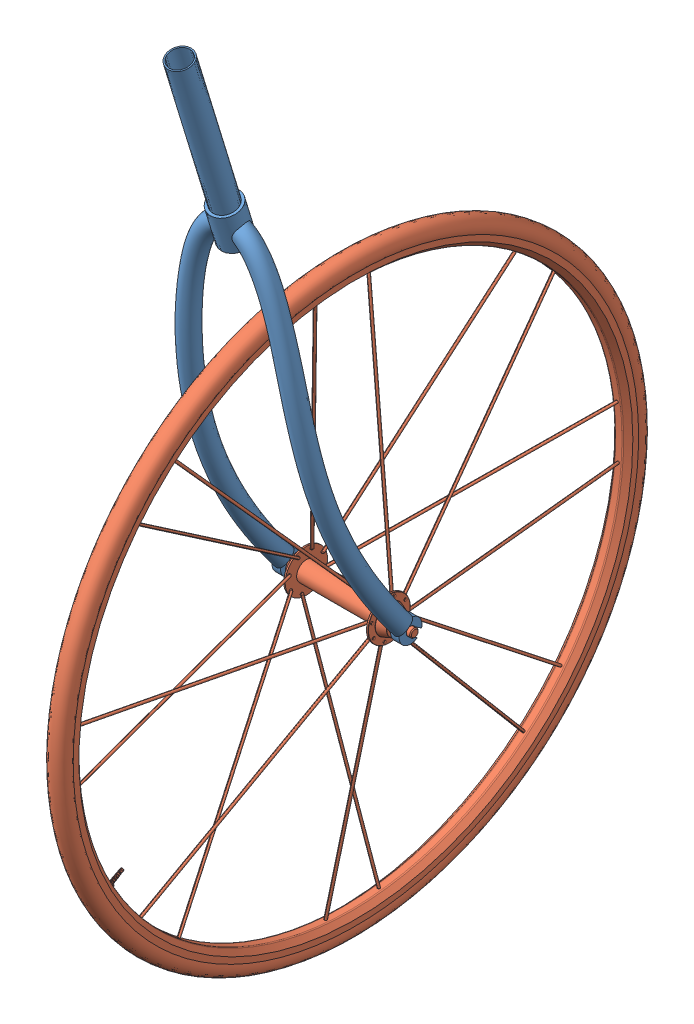
SolidWorks assembly Bike Fork Assembly 2021, configuration Default. Lengths in mm.
Overall size (164.07 1127.04 952.68).
2 component instances, 2 part files, 2 mates.
Components (placement in the parent):
- Bike Fork 2021-1: Bike Fork 2021 [Default] at origin size (164.07 1000.7 700)
- 700c Road Bike Tire1-1: 700c Road Bike Tire1 [Default] x (1 0 0) z (0 0.872686 0.488282) size (160.01 700 700)
Mates (geometry in assembly coordinates):
- Concentric1: concentric aligned: cylinder of Bike Fork 2021-1 through (75 0 0) axis (-1 0 0) radius 4.5; cylinder of 700c Road Bike Tire1-1 through (80 0 0) axis (-1 0 0) radius 5
- Width1: width aligned: plane of 700c Road Bike Tire1-1 through (80 0 0) normal (1 0 0); plane of 700c Road Bike Tire1-1 through (-80 0 0) normal (-1 0 0); plane of Bike Fork 2021-1 through (75 0 0) normal (1 0 0); plane of Bike Fork 2021-1 through (-75 0 0) normal (-1 0 0)
